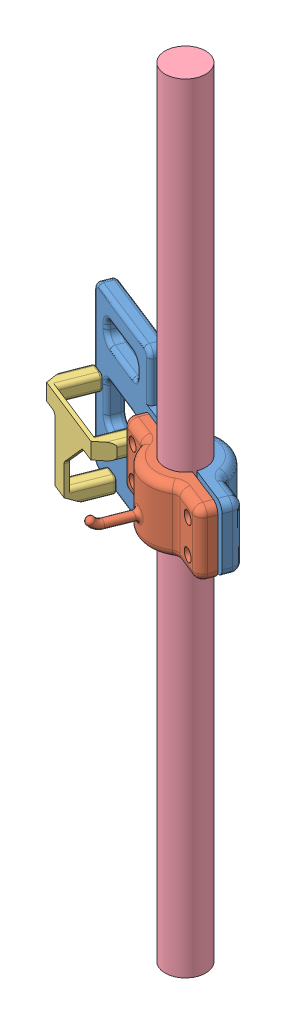
SolidWorks assembly TRIPOD_MOUNT, configuration Default. Lengths in mm.
Overall size (187.9 609.6 148.28).
4 component instances, 4 part files, 10 mates.
Components (placement in the parent):
- TRIPOD_MOUNT_SLED-1: TRIPOD_MOUNT_SLED [Default] at (-78.2229 317.5719 -44.5068) x (0.930248 0 0.366931) z (-0.366931 0 0.930248) size (178.2 127 28.57)
- TRIPOD_MOUNT_CLAMP-1: TRIPOD_MOUNT_CLAMP [Default] at (0 292.1719 0) x (0.930248 0 0.366931) z (-0.366931 0 0.930248) size (102 50.8 58)
- TRIPOD_MOUNT_BRACE-1: TRIPOD_MOUNT_BRACE [Default] at (-93.368 323.9219 -6.1108) x (0.930248 0 0.366931) z (-0.366931 0 0.930248) size (76.2 69.85 31.75)
- TRIPOD_POLE-1: TRIPOD_POLE [Default] at origin size (31.75 609.6 31.75)
Mates (geometry in assembly coordinates):
- Distance1: distance = 2.54 mm anti-aligned: plane of TRIPOD_MOUNT_CLAMP-1 through (-0.932 292.1719 2.3628) normal (0.366931 0 -0.930248); plane of TRIPOD_MOUNT_SLED-1 through (14.7677 292.1719 5.825) normal (-0.366931 0 0.930248)
- Concentric1: concentric aligned: cylinder of TRIPOD_MOUNT_SLED-1 through (46.1114 330.2719 -12.5293) axis (-0.366931 0 0.930248) radius 2.75; cylinder of TRIPOD_MOUNT_CLAMP-1 through (34.6943 330.2719 16.4154) axis (-0.366931 0 0.930248) radius 2.75
- Concentric2: concentric aligned: cylinder of TRIPOD_MOUNT_SLED-1 through (46.1114 304.8719 -12.5293) axis (-0.366931 0 0.930248) radius 2.75; cylinder of TRIPOD_MOUNT_CLAMP-1 through (34.6943 304.8719 16.4154) axis (-0.366931 0 0.930248) radius 2.75
- Concentric3: concentric aligned: cylinder of TRIPOD_MOUNT_SLED-1 through (-51.9496 317.5719 -24.5869) axis (0.366931 0 -0.930248) radius 3; cylinder of TRIPOD_MOUNT_BRACE-1 through (-57.0169 317.5719 -11.7401) axis (0.366931 0 -0.930248) radius 2.5
- Concentric4: concentric aligned: cylinder of TRIPOD_MOUNT_SLED-1 through (-93.2991 260.4219 -40.8969) axis (0.366931 0 -0.930248) radius 3; cylinder of TRIPOD_MOUNT_BRACE-1 through (-98.3664 260.4219 -28.0502) axis (0.366931 0 -0.930248) radius 2.5
- Coincident1: coincident anti-aligned: plane of TRIPOD_MOUNT_SLED-1 through (-82.883 317.5719 -32.6927) normal (-0.366931 0 0.930248); plane of TRIPOD_MOUNT_BRACE-1 through (-82.883 323.9219 -32.6927) normal (0.366931 0 -0.930248)
- Concentric5: concentric anti-aligned: cylinder of TRIPOD_MOUNT_SLED-1 through (0 292.1719 0) axis (0 1 0) radius 15.875; cylinder of TRIPOD_POLE-1 through (0 609.6 0) axis (0 -1 0) radius 15.875
- Coincident2: coincident aligned: plane of TRIPOD_POLE-1 through (0 0 0) normal (0 0 1)
- Coincident3: coincident aligned: plane of TRIPOD_POLE-1 through (0 0 0) normal (0 1 0)
- Coincident4: coincident aligned: plane of TRIPOD_POLE-1 through (0 0 0) normal (1 0 0)
